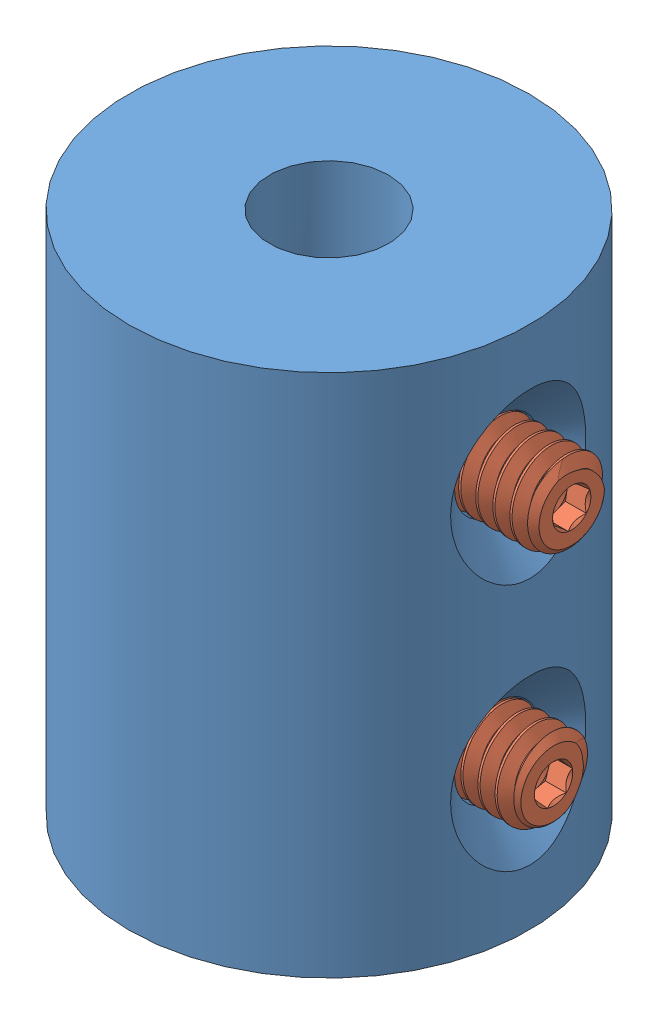
SolidWorks assembly 0.125_0.5_Coupler, configuration Default. Lengths in mm.
Overall size (11.98 13.97 10.67).
3 component instances, 2 part files, 4 mates.
Components (placement in the parent):
- 0.125_0.5_Coupler-1: 0.125_0.5_Coupler [Default] at (3.095 2.7029 14.9583) size (10.67 13.97 10.67)
- 97705A142-1: 97705A142 [97705A142] at (7.3322 12.9938 14.9389) x (-0.004504 -0.175182 -0.984526) z (0.99999 0 -0.004574) size (2.52 2.21 4.96)
- 97705A142-2: 97705A142 [97705A142] at (6.8507 6.382 14.9411) x (-0.000926 -0.979309 -0.202367) z (0.99999 0 -0.004574) size (2.52 2.21 4.96)
Mates (geometry in assembly coordinates):
- Concentric1: concentric aligned: circle of 0.125_0.5_Coupler-1; circle of 97705A142-1
- Concentric2: concentric aligned: circle of 0.125_0.5_Coupler-1; circle of 97705A142-2
- Screw1: screw = 56 anti-aligned: circle of 0.125_0.5_Coupler-1; cone of 97705A142-2 through (4.2897 6.382 14.9528) axis (-0.99999 0 0.004574)
- Screw2: screw = 56 anti-aligned: circle of 0.125_0.5_Coupler-1; cone of 97705A142-1 through (4.7712 12.9938 14.9506) axis (-0.99999 0 0.004574)
